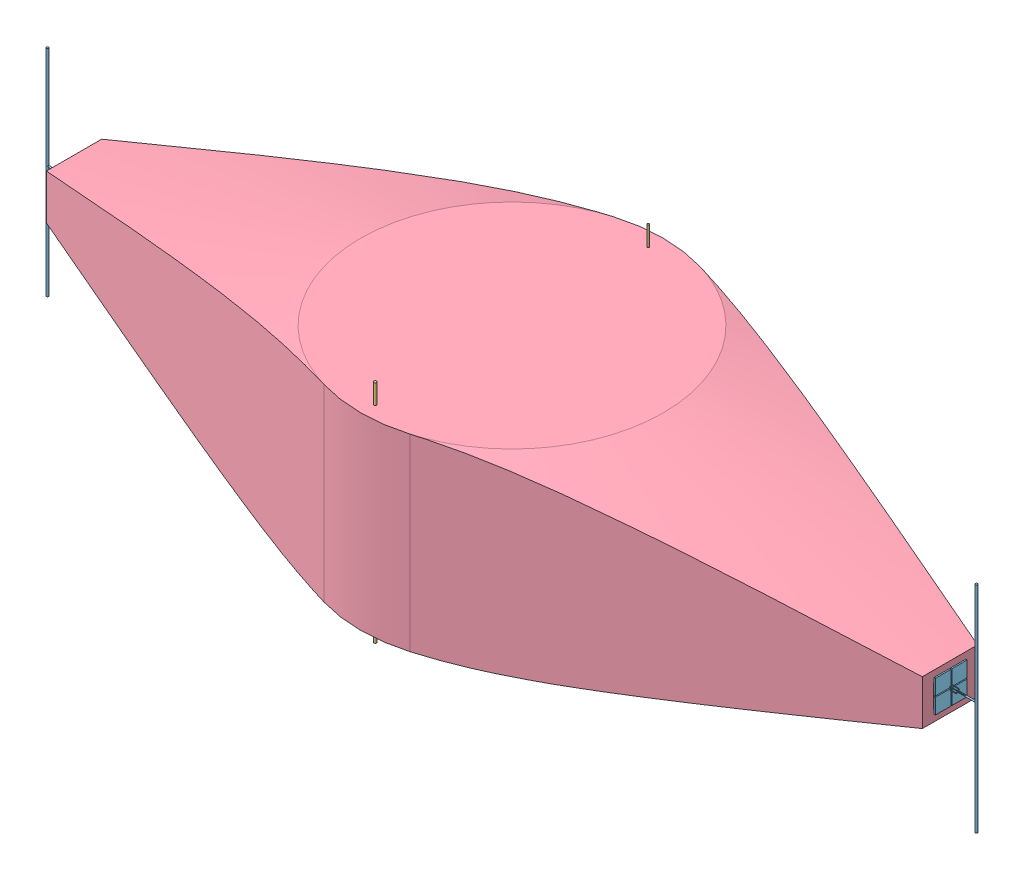
SolidWorks assembly Unit, configuration 默认. Lengths in mm.
Overall size (350.8 85.25 116.67).
6 component instances, 5 part files, 11 mates.
Components (placement in the parent):
- BEGeDet-1: BEGeDet [默认] at (-1.1221 -39.076 80) size (80 40 80)
- InnerShell-3: InnerShell [默认] at (-1.1221 11.4233 80) x (-1 0 0) z (0 0 1) size (102 61 102)
- Electronics-1: Electronics [默认] at (-1.1221 -49.676 80) size (21.21 85 103.7)
- OuterShell-2: OuterShell [默认] at (-1.1221 -55.5767 80) size (330 72.56 116.67)
- SiPMArray-4: SiPMArray [默认] at (163.8779 -19.9292 80) size (10.4 81 12)
- SiPMArray-6: SiPMArray [默认] at (-166.1221 -19.9292 80) x (-1 0 0) z (0 0 -1) size (10.4 81 12)
Mates (geometry in assembly coordinates):
- 同心1: concentric aligned: circle of BEGeDet-1; circle of InnerShell-3
- 轮廓中心1: profile center anti-aligned: circle of BEGeDet-1; circle of Electronics-1
- 同心11: concentric aligned: cylinder of BEGeDet-1 through (-1.1221 0.924 80) axis (0 -1 0) radius 40; cylinder of OuterShell-2 through (-1.1221 113.4233 80) axis (0 -1 0) radius 57
- 重合23: coincident anti-aligned: plane of InnerShell-3; plane of OuterShell-2 through (-1.1221 11.4233 80) normal (0 -1 0)
- 平行14: parallel anti-aligned: line of OuterShell-2 through (163.8779 -15.5385 73.7665) axis (0 -1 0); line of SiPMArray-4 through (163.8779 -19.7292 74) axis (0 1 0)
- 重合45: coincident anti-aligned: plane of OuterShell-2 through (163.8779 104.4233 90.4066) normal (1 0 0); plane of SiPMArray-4 through (163.8779 -19.9292 80) normal (-1 0 0)
- 重合46: coincident: point of SiPMArray-4; point of assembly
- 重合47: coincident: point of SiPMArray-6; point of assembly
- 平行16: parallel anti-aligned: line of OuterShell-2 through (-166.1221 -11.4693 90.4066) axis (0 -1 0); line of SiPMArray-6 through (-166.6221 -25.9292 86) axis (0 1 0)
- 平行17: parallel aligned: plane of OuterShell-2 through (-166.1221 104.4233 69.5934) normal (-1 0 0); plane of SiPMArray-6 through (-166.6221 -19.9292 80) normal (-1 0 0)
- 平行18: parallel anti-aligned: plane of Electronics-1 through (-1.3221 -49.676 80) normal (-1 0 0); plane of OuterShell-2 through (163.8779 104.4233 90.4066) normal (1 0 0)
